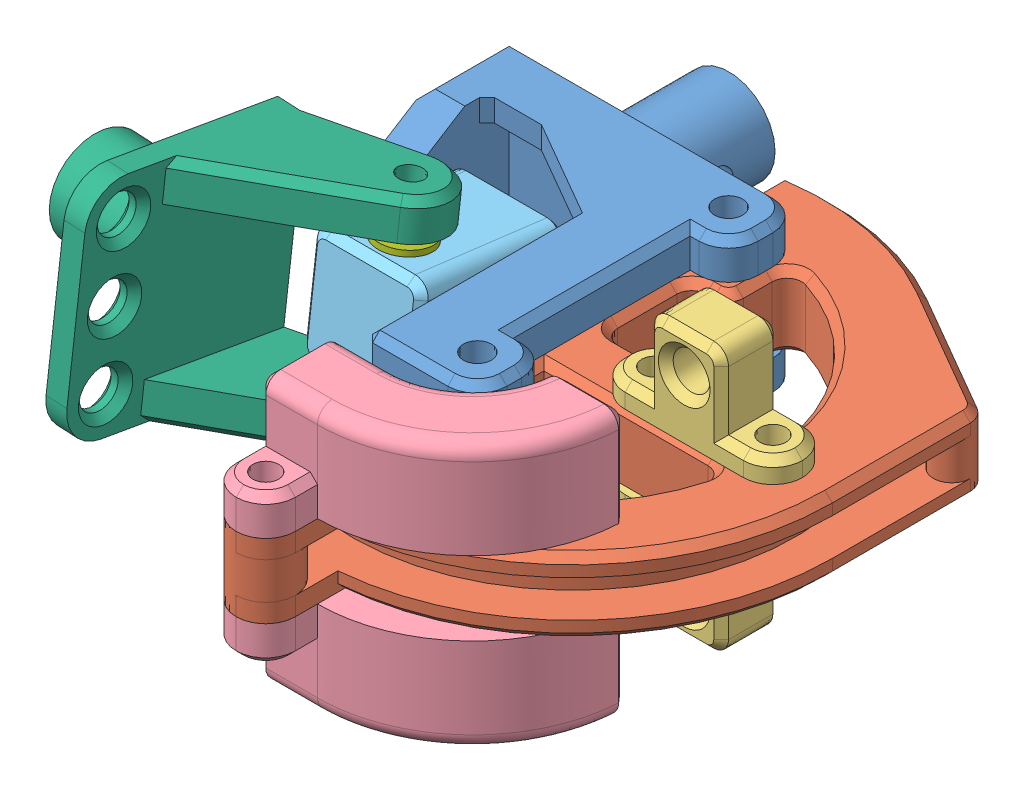
SolidWorks assembly shoulder, configuration ﾃﾞﾌｫﾙﾄ. Lengths in mm.
12 component instances, 7 part files, 39 mates.
Components (placement in the parent):
- shoulder_joint_connector-1: shoulder_joint_connector [outer] at origin size (39.7 24.5 59)
- shoulder_joint_circle-1: shoulder_joint_circle [ﾃﾞﾌｫﾙﾄ] at (19.95 4.65 26) x (1 0 0) z (0 -1 0) size (40 79.64 10)
- shoulder_fromknee_middle-2: shoulder_fromknee_middle [ﾃﾞﾌｫﾙﾄ] at (38.95 -5.35 26) x (1 0 0) z (0 1 0) size (24 8 13)
- shoulder_fromknee_middle-3: shoulder_fromknee_middle [ﾃﾞﾌｫﾙﾄ] at (38.95 4.65 26) x (1 0 0) z (0 -1 0) size (24 8 13)
- shoulder_fromknee_middle_curve-4: shoulder_fromknee_middle_curve [ﾃﾞﾌｫﾙﾄ] at (18.95 -5.35 58.641) x (0 0 1) z (0 1 0) size (28 28.97 13)
- shoulder2-1: shoulder2 [ﾃﾞﾌｫﾙﾄ] at (0 -0.6236 15.039) x (1 0 0) z (0 0.124725 0.992191) size (15 15 20)
- shoulder3-1: shoulder3 [ﾃﾞﾌｫﾙﾄ] at (-33.4672 2.1287 36.9342) x (0 -0.992191 0.124725) z (0.998311 0.007247 0.057647) size (29.5 33 38)
- bearing-1: bearing [ﾃﾞﾌｫﾙﾄ] at (-8.25 0 20) x (0 -0.741073 -0.671424) z (0 -0.671424 0.741073) size (7 5 7)
- bearing-2: bearing [ﾃﾞﾌｫﾙﾄ] at (8.25 0 20) x (0 0.996554 -0.08295) z (0 0.08295 0.996554) size (7 5 7)
- bearing-3: bearing [ﾃﾞﾌｫﾙﾄ] at (0 -6.9383 30.9509) x (0.947814 -0.039765 -0.316333) z (0.318822 0.118216 0.940413) size (7 5 7)
- bearing-4: bearing [ﾃﾞﾌｫﾙﾄ] at (0 9.4328 28.8929) x (-0.839936 -0.067687 -0.538447) z (-0.542685 0.104761 0.833378) size (7 5 7)
- shoulder_fromknee_middle_curve-5: shoulder_fromknee_middle_curve [mirror] at (18.95 4.65 58.641) x (0 0 1) z (0 1 0) size (28 28.97 13)
Mates (geometry in assembly coordinates):
- 一致1: coincident anti-aligned: plane of shoulder_joint_connector-1 through (24.95 -5.35 0) normal (0 1 0); plane of shoulder_joint_circle-1 through (19.95 -5.35 26) normal (0 -1 0)
- 同心円3: concentric aligned: cylinder of shoulder_joint_circle-1 through (29 31.2488 23) axis (0 -1 0) radius 1.75; cylinder of shoulder_fromknee_middle-1 through (25.5 -5 23) axis (0 -1 0) radius 1.75
- 同心円4: concentric aligned: cylinder of shoulder_joint_circle-1 through (43 31.2488 23) axis (0 -1 0) radius 1.75; cylinder of shoulder_fromknee_middle-1 through (39.5 -5 23) axis (0 -1 0) radius 1.75
- 一致5: coincident anti-aligned: plane of shoulder_joint_circle-1 through (19.95 -5.35 26) normal (0 -1 0); plane of shoulder_fromknee_middle-1 through (22.5 -5 19) normal (0 1 0)
- 同心円5: concentric anti-aligned: cylinder of shoulder_joint_circle-1 through (43 31.2488 23) axis (0 -1 0) radius 1.75; cylinder of shoulder_fromknee_middle_simple-1 through (39.5 5 23) axis (0 1 0) radius 1.75
- 同心円6: concentric anti-aligned: cylinder of shoulder_joint_circle-1 through (29 31.2488 23) axis (0 -1 0) radius 1.75; cylinder of shoulder_fromknee_middle_simple-1 through (25.5 5 23) axis (0 1 0) radius 1.75
- 一致6: coincident anti-aligned: plane of shoulder_joint_circle-1 through (19.95 4.65 26) normal (0 1 0); plane of shoulder_fromknee_middle_simple-1 through (21.5 5 27) normal (0 -1 0)
- 一致7: coincident anti-aligned: plane of shoulder_joint_circle-1 through (19.95 -5.35 26) normal (0 -1 0); plane of shoulder_fromknee_middle_simple-2 through (43.5 -5 27) normal (0 1 0)
- 同心円7: concentric aligned: cylinder of shoulder_joint_circle-1 through (43 31.2488 23) axis (0 -1 0) radius 1.75; cylinder of shoulder_fromknee_middle_simple-2 through (39.5 -5 23) axis (0 -1 0) radius 1.75
- 同心円8: concentric aligned: cylinder of shoulder_joint_circle-1 through (29 31.2488 23) axis (0 -1 0) radius 1.75; cylinder of shoulder_fromknee_middle_simple-2 through (25.5 -5 23) axis (0 -1 0) radius 1.75
- 一致8: coincident anti-aligned: plane of shoulder_joint_circle-1 through (19.95 -5.35 26) normal (0 -1 0); plane of shoulder_fromknee_middle-2 through (26.95 -5.35 22) normal (0 1 0)
- 一致9: coincident anti-aligned: plane of shoulder_joint_circle-1 through (19.95 4.65 26) normal (0 1 0); plane of shoulder_fromknee_middle-3 through (26.95 4.65 30) normal (0 -1 0)
- 同心円13: concentric aligned: cylinder of shoulder_joint_circle-1 through (18.95 -2.85 66.641) axis (0 -1 0) radius 1.75; cylinder of shoulder_fromknee_middle_curve-4 through (18.95 -5.35 66.641) axis (0 -1 0) radius 1.75
- 同心円14: concentric aligned: cylinder of shoulder_joint_circle-1 through (18.95 4.65 50.641) axis (0 -1 0) radius 1.75; cylinder of shoulder_fromknee_middle_curve-4 through (18.95 -5.35 50.641) axis (0 -1 0) radius 1.75
- 一致10: coincident anti-aligned: plane of shoulder_joint_circle-1 through (19.95 -5.35 26) normal (0 -1 0); plane of shoulder_fromknee_middle_curve-4 through (22.95 -5.35 46.641) normal (0 1 0)
- 同心円15: concentric anti-aligned: cylinder of shoulder_joint_circle-1 through (18.95 -2.85 66.641) axis (0 -1 0) radius 1.75; cylinder of shoulder_fromknee_middle-5 through (18.95 4.65 66.641) axis (0 1 0) radius 1.75
- 一致11: coincident anti-aligned: plane of shoulder_joint_circle-1 through (19.95 4.65 26) normal (0 1 0); plane of shoulder_fromknee_middle-5 through (14.95 4.65 46.641) normal (0 -1 0)
- 同心円16: concentric anti-aligned: cylinder of shoulder_joint_circle-1 through (18.95 4.65 50.641) axis (0 -1 0) radius 1.75; cylinder of shoulder_fromknee_middle-5 through (18.95 4.65 50.641) axis (0 1 0) radius 1.75
- 同心円17: concentric anti-aligned: cylinder of shoulder_joint_circle-1 through (46.95 4.65 26) axis (0 -1 0) radius 1.75; cylinder of shoulder_fromknee_middle-3 through (46.95 4.65 26) axis (0 1 0) radius 1.75
- 同心円18: concentric anti-aligned: cylinder of shoulder_joint_circle-1 through (30.95 4.65 26) axis (0 -1 0) radius 1.75; cylinder of shoulder_fromknee_middle-3 through (30.95 4.65 26) axis (0 1 0) radius 1.75
- 同心円19: concentric aligned: cylinder of shoulder_joint_circle-1 through (46.95 4.65 26) axis (0 -1 0) radius 1.75; cylinder of shoulder_fromknee_middle-2 through (46.95 -5.35 26) axis (0 -1 0) radius 1.75
- 同心円20: concentric aligned: cylinder of shoulder_joint_circle-1 through (30.95 4.65 26) axis (0 -1 0) radius 1.75; cylinder of shoulder_fromknee_middle-2 through (30.95 -5.35 26) axis (0 -1 0) radius 1.75
- 同心円23: concentric anti-aligned: cylinder of shoulder2-1 through (0 -6.1942 30.8574) axis (0 0.992191 -0.124725) radius 2.45; cylinder of shoulder3-1 through (0 -8.4266 31.138) axis (0 -0.992191 0.124725) radius 1.65
- 幅2: width anti-aligned: plane of shoulder3-1 through (0 10.9211 28.7058) normal (0 -0.992191 0.124725); plane of shoulder3-1 through (0 -8.4266 31.138) normal (0 0.992191 -0.124725); plane of shoulder2-1 through (-7.5 9.3123 33.9474) normal (0 0.992191 -0.124725); plane of shoulder2-1 through (-7.5 -5.5706 35.8183) normal (0 -0.992191 0.124725)
- 同心円25: concentric aligned: cylinder of shoulder2-1 through (-7.5 0 20) axis (1 0 0) radius 2.45; cylinder of bearing-2 through (8.25 0 20) axis (1 0 0) radius 1.5
- 一致12: coincident anti-aligned: plane of shoulder2-1 through (7.5 9.3123 33.9474) normal (1 0 0); plane of bearing-2 through (7.5 3.4879 19.7097) normal (-1 0 0)
- 同心円26: concentric anti-aligned: cylinder of shoulder2-1 through (-7.5 0 20) axis (1 0 0) radius 2.45; cylinder of bearing-1 through (-8.25 0 20) axis (-1 0 0) radius 2.25
- 一致13: coincident anti-aligned: plane of shoulder2-1 through (-7.5 9.3123 33.9474) normal (-1 0 0); plane of bearing-1 through (-7.5 -2.5938 17.65) normal (1 0 0)
- 同心円27: concentric anti-aligned: cylinder of shoulder2-1 through (0 -6.1942 30.8574) axis (0 0.992191 -0.124725) radius 2.45; cylinder of bearing-3 through (0 -6.9383 30.9509) axis (0 -0.992191 0.124725) radius 2.25
- 一致14: coincident anti-aligned: plane of shoulder2-1 through (-7.5 -5.5706 35.8183) normal (0 -0.992191 0.124725); plane of bearing-3 through (3.3174 -6.3334 29.7502) normal (0 0.992191 -0.124725)
- 同心円29: concentric aligned: cylinder of shoulder2-1 through (0 -6.1942 30.8574) axis (0 0.992191 -0.124725) radius 2.45; cylinder of bearing-4 through (0 9.4328 28.8929) axis (0 0.992191 -0.124725) radius 2.25
- 一致15: coincident anti-aligned: plane of shoulder2-1 through (-7.5 9.3123 33.9474) normal (0 0.992191 -0.124725); plane of bearing-4 through (-2.9398 8.4518 27.1019) normal (0 -0.992191 0.124725)
- 同心円30: concentric aligned: cylinder of shoulder_joint_connector-1 through (19.95 10.35 5) axis (0 -1 0) radius 1.9; cylinder of shoulder_joint_circle-1 through (19.95 4.65 5) axis (0 -1 0) radius 1.75
- 同心円31: concentric aligned: cylinder of shoulder_joint_connector-1 through (19.95 10.35 39) axis (0 -1 0) radius 1.9; cylinder of shoulder_joint_circle-1 through (19.95 4.65 39) axis (0 -1 0) radius 1.75
- 同心円32: concentric aligned: cylinder of shoulder_joint_connector-1 through (9.75 0 20) axis (1 0 0) radius 1.75; cylinder of shoulder2-1 through (-7.5 0 20) axis (1 0 0) radius 2.45
- 幅3: width anti-aligned: plane of shoulder_joint_connector-1 through (-9.75 0 20) normal (1 0 0); plane of shoulder2-1 through (9.75 0 0) normal (-1 0 0); plane of shoulder_joint_connector-1 through (-7.5 9.3123 33.9474) normal (-1 0 0); plane of shoulder2-1 through (7.5 9.3123 33.9474) normal (1 0 0)
- 同心円33: concentric: cylinder of shoulder_joint_circle-1 through (18.95 -2.85 66.641) axis (0 -1 0) radius 1.75; cylinder of shoulder_fromknee_middle_curve-5 through (18.95 4.65 66.641) axis (0 1 0) radius 1.75
- 同心円34: concentric: cylinder of shoulder_joint_circle-1 through (18.95 4.65 50.641) axis (0 -1 0) radius 1.75; cylinder of shoulder_fromknee_middle_curve-5 through (18.95 4.65 50.641) axis (0 1 0) radius 1.75
- 一致16: coincident anti-aligned: plane of shoulder_joint_circle-1 through (19.95 4.65 26) normal (0 1 0); plane of shoulder_fromknee_middle_curve-5 through (22.95 4.65 46.641) normal (0 -1 0)
